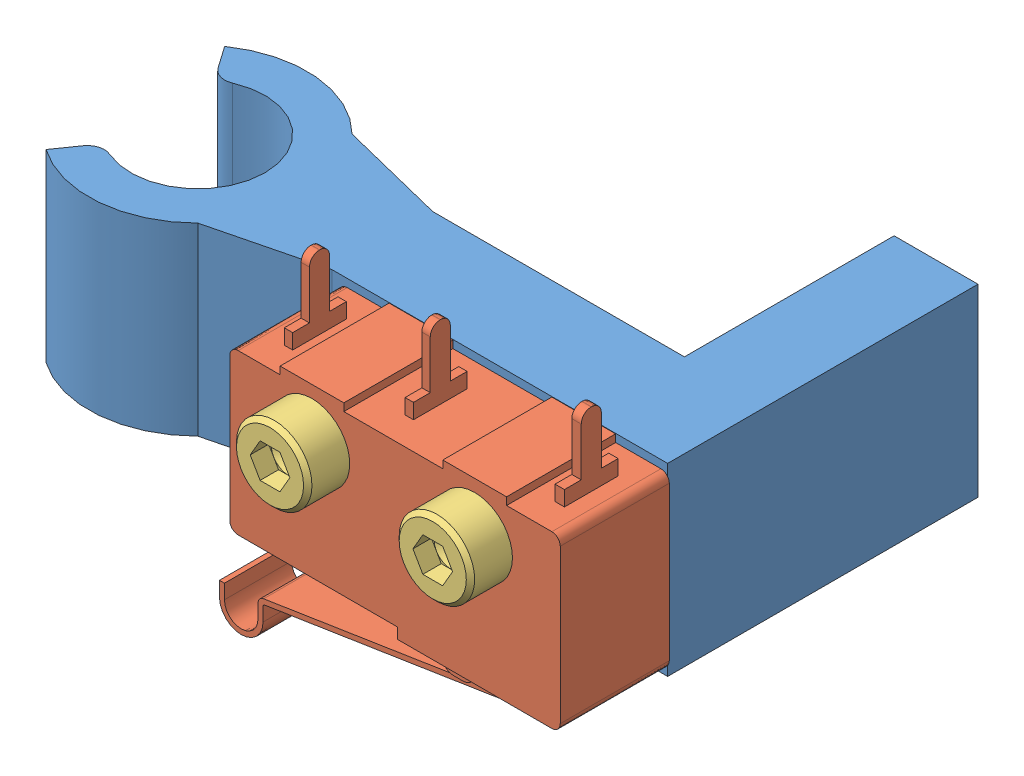
SolidWorks assembly x_endstop, configuration Défaut. Lengths in mm.
Overall size (34.83 20.24 27.5).
4 component instances, 3 part files, 9 mates.
Components (placement in the parent):
- x_endstop-1: x_endstop [Défaut] at origin size (34.73 11 22)
- kw4A(S) microswitch-1: kw4A(S) microswitch [Default] at (21.15 10.525 3) x (0 0 1) z (1 0 0) size (6.5 20.24 21.62)
- socket head cap screw_am-1: socket head cap screw_am [B18.3.1M - 2.5 x 0.45 x 10 Hex SHCS -- 10NHX] at (16.3 8 12) x (0 0 -1) z (0 -1 0) size (12.5 4.5 4.5)
- socket head cap screw_am-3: socket head cap screw_am [B18.3.1M - 2.5 x 0.45 x 10 Hex SHCS -- 10NHX] at (26 8 12) x (0 0 -1) z (-0.866025 0.5 0) size (12.5 4.5 4.5)
Mates (geometry in assembly coordinates):
- Coïncidente1: coincident anti-aligned: plane of x_endstop-1 through (0 11 3) normal (0 0 1); plane of kw4A(S) microswitch-1 through (11.9 1.505 3) normal (0 0 -1)
- Coaxiale4: concentric anti-aligned: cylinder of kw4A(S) microswitch-1 through (16.3 8 9.5) axis (0 0 -1) radius 1.275; cylinder of socket head cap screw_am-1 through (16.3 8 43.75) axis (0 0 1) radius 1.25
- Coïncidente2: coincident anti-aligned: plane of kw4A(S) microswitch-1 through (11.9 1.505 9.5) normal (0 0 1); plane of socket head cap screw_am-1 through (18.55 8 9.5) normal (0 0 -1)
- Coaxiale6: concentric anti-aligned: cylinder of kw4A(S) microswitch-1 through (26 8 9.5) axis (0 0 -1) radius 1.275; cylinder of socket head cap screw_am-3 through (26 8 43.75) axis (0 0 1) radius 2.25
- Coïncidente4: coincident anti-aligned: plane of kw4A(S) microswitch-1 through (11.9 1.505 9.5) normal (0 0 1); plane of socket head cap screw_am-3 through (24.875 6.0514 9.5) normal (0 0 -1)
- Parallèle5: parallel aligned: plane of socket head cap screw_am-1 through (16.8903 9.0225 10.9) normal (0 -1 0); plane of socket head cap screw_am-3 through (25.4097 9.0225 10.9) normal (0 -1 0)
- Parallèle6: parallel aligned: plane of kw4A(S) microswitch-1 through (30.6 0.365 9.5) normal (0 -1 0); plane of socket head cap screw_am-3 through (25.4097 9.0225 10.9) normal (0 -1 0)
- Coaxiale7: concentric aligned: cylinder of x_endstop-1 through (16.3 8 -1) axis (0 0 1) radius 1; circle of kw4A(S) microswitch-1
- Coaxiale8: concentric aligned: circle of x_endstop-1; circle of kw4A(S) microswitch-1
